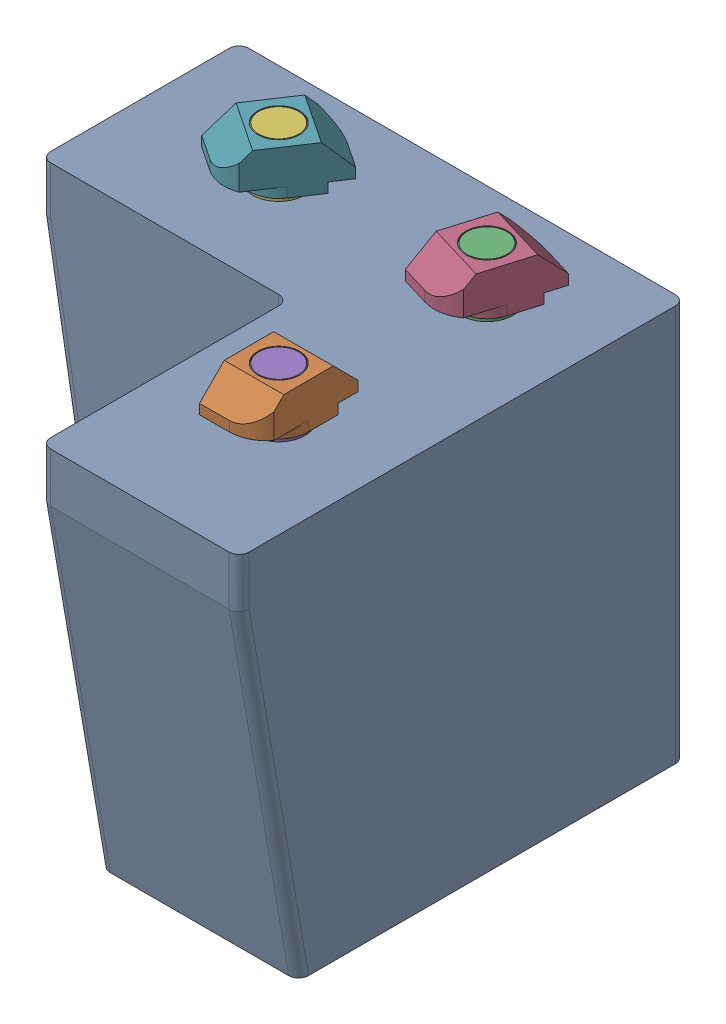
SolidWorks assembly front_right_foot, configuration Default. Lengths in mm.
Overall size (45 45 45).
7 component instances, 3 part files, 0 mates.
Components (placement in the parent):
- budget_foot_Front Right Foot-1: budget_foot_Front Right Foot [Default] at (477.3115 276.9149 684.384) x (-1 0 0) z (0 0 -1) size (45 40 45)
- m5_locking_t_nut_20x20_generic-1: m5_locking_t_nut_20x20_generic [Default] at (470.3115 281.9149 715.3757) x (-0.002757 0 -0.999996) z (-0.999996 0 0.002757) size (10 4.5 6)
- m5_low_profile_screw_template_M5 x 10-1: m5_low_profile_screw_template_M5 x 10 [Default] at (467.3115 281.9149 694.384) x (0 1 0) z (-0.452256 0 0.891888) size (11.62 9 9)
- m5_locking_t_nut_20x20_generic-2: m5_locking_t_nut_20x20_generic [Default] at (470.1858 281.9149 695.2433) x (0.286428 0 -0.958102) z (-0.958102 0 -0.286428) size (10 4.5 6)
- m5_low_profile_screw_template_M5 x 10-2: m5_low_profile_screw_template_M5 x 10 [Default] at (467.3115 281.9149 715.384) x (0 1 0) z (-0.452256 0 0.891888) size (11.62 9 9)
- m5_low_profile_screw_template_M5 x 10-3: m5_low_profile_screw_template_M5 x 10 [Default] at (446.3115 281.9149 694.384) x (0 1 0) z (-0.452256 0 0.891888) size (11.62 9 9)
- m5_locking_t_nut_20x20_generic-3: m5_locking_t_nut_20x20_generic [Default] at (448.8082 281.9149 696.0472) x (0.554401 0 -0.83225) z (-0.83225 0 -0.554401) size (10 4.5 6)
